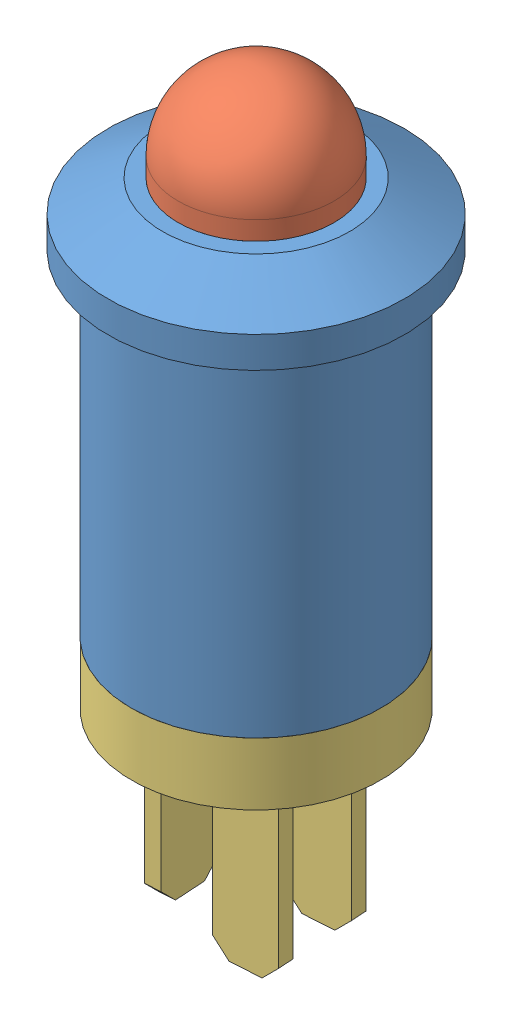
SolidWorks assembly LED_8mm, configuration Default. Lengths in mm.
Overall size (9.5 23.85 9.5).
3 component instances, 3 part files, 3 mates.
Components (placement in the parent):
- Suporte_LED-1: Suporte_LED [Default] at (0.8006 -5.901 3.5866) size (9.5 12.75 9.5)
- LED-1: LED [Default] at (0.8006 7.449 3.5866) size (5 3.1 5)
- Conexao-1: Conexao [Default] at (0.8006 -7.901 3.5866) x (0.063421 0 0.997987) z (-0.997987 0 0.063421) size (8 8 8)
Mates (geometry in assembly coordinates):
- Coincident1: coincident aligned: circle of Suporte_LED-1; circle of LED-1
- Concentric1: concentric: cylinder of Suporte_LED-1 through (0.8006 -29.9124 3.5866) axis (0 -1 0) radius 3; cylinder of Conexao-1 through (0.8006 -13.9398 3.5866) axis (0 -1 0) radius 4
- Coincident2: coincident anti-aligned: plane of Suporte_LED-1 through (4.8006 -5.901 3.5866) normal (0 -1 0); plane of Conexao-1 through (0.8006 -5.901 3.5866) normal (0 1 0)
